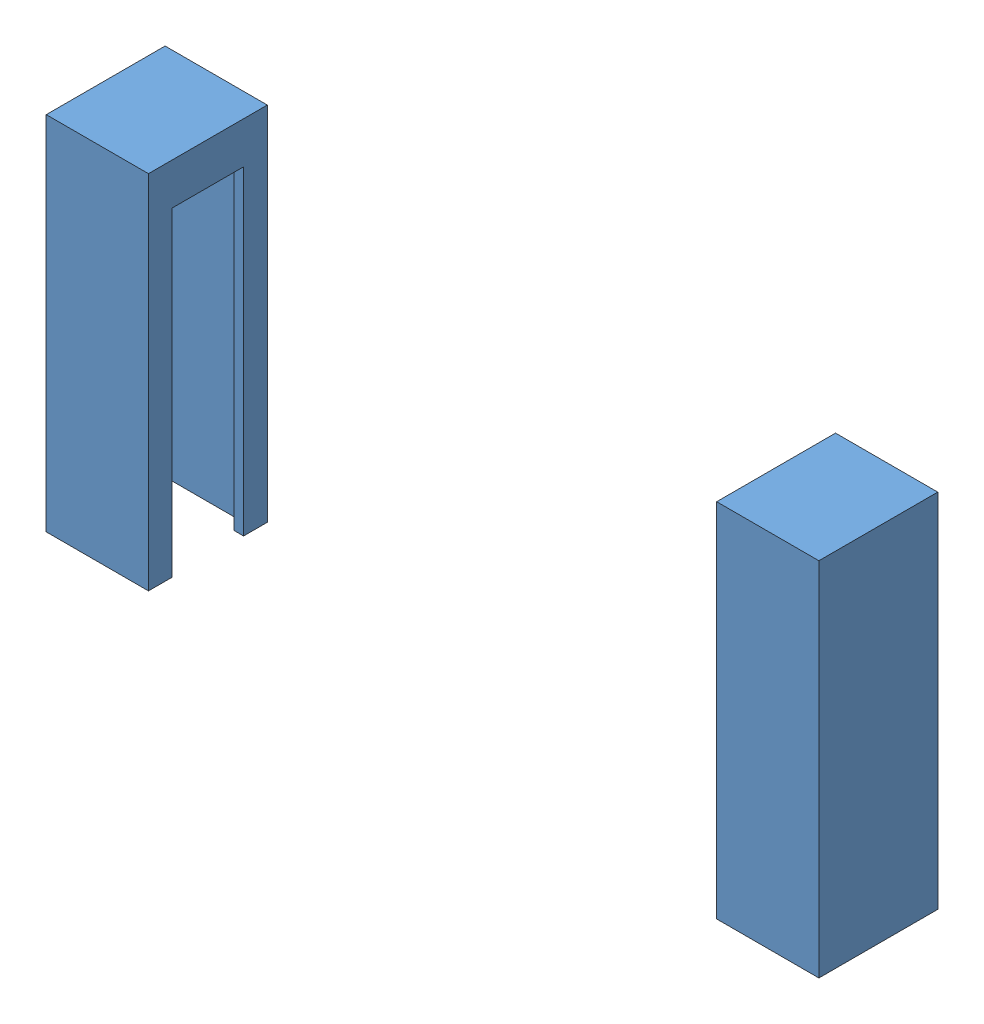
SolidWorks assembly preferenceV2_dispenser_IRAssembly - Copy, configuration Default. Lengths in mm.
Overall size (32.5 15.2 5).
4 component instances, 1 part files, 3 mates.
Components (placement in the parent):
- sparkfunIR_LEDandCase-1: sparkfunIR_LEDandCase [2Pin] at (-11.0025 21.2786 44.4241) x (-1 0 0) z (0 0 -1) size (4.3 15.2 5)
  - sparkfunIR_casing-1: sparkfunIR_casing [Default] at (-40.6525 -5.8286 32.4491) x (1 0 0) z (0 0 -1) size (4.3 15.2 5)
- sparkfunIR_LEDandCase-2: sparkfunIR_LEDandCase [3Pin] at (42.1025 21.2786 -20.4741) size (4.3 15.2 5)
  - sparkfunIR_casing-1: sparkfunIR_casing [Default] at (-40.6525 -5.8286 32.4491) x (1 0 0) z (0 0 -1) size (4.3 15.2 5)
Mates (geometry in assembly coordinates):
- Distance1: distance = 32.5 mm anti-aligned: plane of sparkfunIR_LEDandCase-2/sparkfunIR_casing-1 through (-0.7 15.45 9.475) normal (-1 0 0); plane of sparkfunIR_LEDandCase-1/sparkfunIR_casing-1 through (31.8 15.45 14.475) normal (1 0 0)
- Coincident2: coincident aligned: plane of sparkfunIR_LEDandCase-1/sparkfunIR_casing-1 through (29.65 15.45 14.475) normal (0 0 1); plane of sparkfunIR_LEDandCase-2/sparkfunIR_casing-1 through (-7.15 15.45 14.475) normal (0 0 1)
- Coincident3: coincident aligned: plane of sparkfunIR_LEDandCase-1/sparkfunIR_casing-1 through (31.8 0.25 14.475) normal (0 -1 0); plane of sparkfunIR_LEDandCase-2/sparkfunIR_casing-1 through (-9.3 0.25 9.475) normal (0 -1 0)
